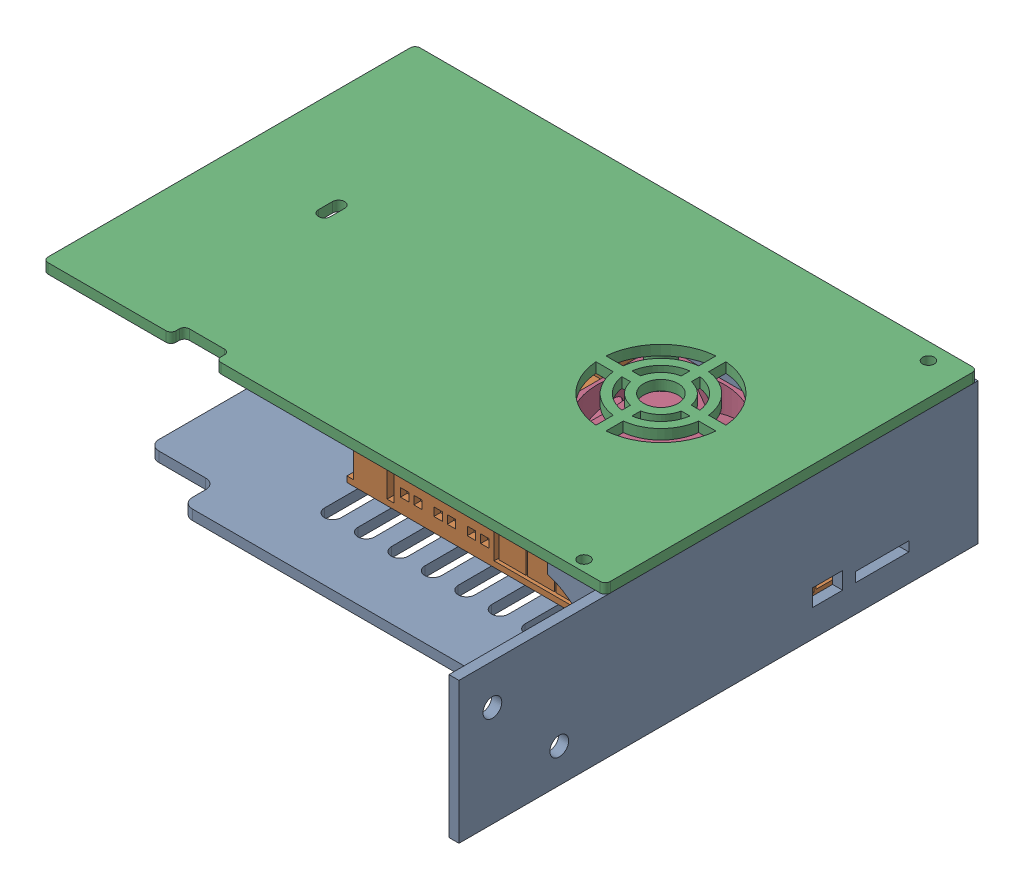
SolidWorks assembly mont_motherboard, configuration Valor predeterminado. Lengths in mm.
Overall size (168.11 56.79 155.2).
4 component instances, 4 part files, 11 mates.
Components (placement in the parent):
- Sheetmetal enclosure bottom-1: Sheetmetal enclosure bottom [Valor predeterminado] at (4.2723 -34.7148 0) size (146.46 42.2 155.2)
- Control panel-1: Control panel [Standard] at (-85.7977 -68.8148 -22.73) x (0 0 1) z (0 -1 0) size (70 100 20)
- Sheetmetal enclosure top-2: Sheetmetal enclosure top [Valor predeterminado] at (-5.0527 4.4852 -1.3999) x (0 0 -1) z (1 0 0) size (111.26 7.2 168.11)
- Case fan-1: Case fan [Standard] at (-70.2994 -27.3175 -12.3561) x (1 0 0) z (0 -0.573576 0.819152) size (40 31.13 38.5)
Mates (geometry in assembly coordinates):
- Concêntrico1: concentric anti-aligned: circle of Sheetmetal enclosure bottom-1; circle of Control panel-1
- Coincidente1: coincident anti-aligned: plane of Sheetmetal enclosure bottom-1 through (-22.1977 -30.5148 -3.63) normal (0 1 0); plane of Control panel-1 through (26.0023 -30.5148 -6.53) normal (0 -1 0)
- Concêntrico6: concentric anti-aligned: circle of Sheetmetal enclosure top-1; circle of Case fan-1
- Concêntrico7: concentric anti-aligned: circle of Sheetmetal enclosure top-1; circle of Case fan-1
- Coincidente3: coincident anti-aligned: plane of Sheetmetal enclosure top-1 through (21.8923 0.2852 -19.5299) normal (0 -1 0); plane of Case fan-1 through (37.8923 0.2852 -3.5299) normal (0 1 0)
- Concêntrico9: concentric aligned: circle of Sheetmetal enclosure bottom-1; circle of Sheetmetal enclosure top-2
- Concêntrico10: concentric aligned: circle of Sheetmetal enclosure bottom-1; circle of Sheetmetal enclosure top-2
- Coincidente4: coincident anti-aligned: plane of Sheetmetal enclosure bottom-1 through (76.0023 4.4852 -57.23) normal (0 1 0); plane of Sheetmetal enclosure top-2 through (-5.0527 4.4852 -1.3999) normal (0 -1 0)
- Concêntrico11: concentric: circle of Sheetmetal enclosure top-2; circle of Case fan-1
- Concêntrico12: concentric: circle of Sheetmetal enclosure top-2; circle of Case fan-1
- Coincidente8: coincident anti-aligned: plane of Sheetmetal enclosure top-2 through (53.8923 0.2852 12.4701) normal (0 -1 0); plane of Case fan-1 through (37.8923 0.2852 -3.5299) normal (0 1 0)
